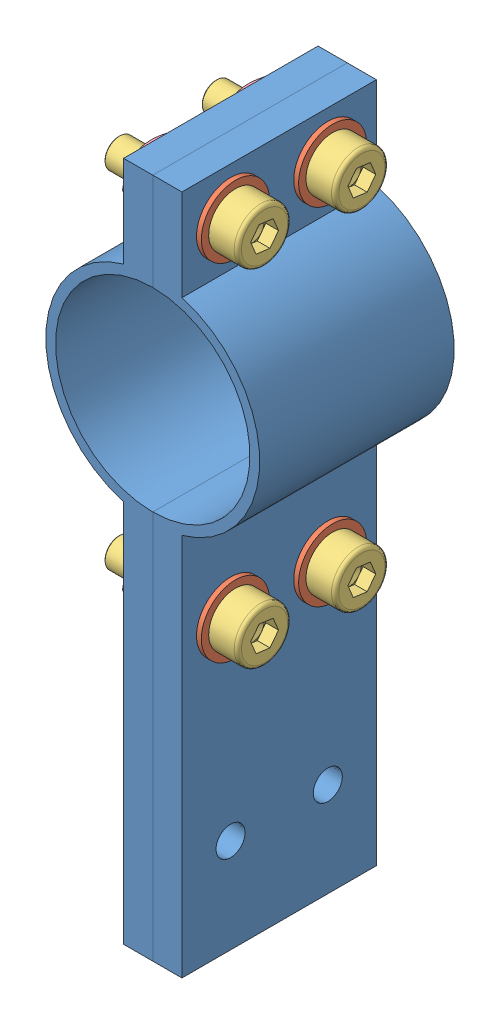
SolidWorks assembly 小管夹具, configuration 默认. Lengths in mm.
Overall size (22 70 20).
14 component instances, 4 part files, 28 mates.
Components (placement in the parent):
- 夹具-1: 夹具 [默认] at (55.615 31.0944 -10) size (11 70 20)
- 夹具-2: 夹具 [默认] at (55.615 31.0944 10) x (-1 0 0) z (0 0 -1) size (11 70 20)
- plain washers-n series-grade a gb-2: plain washers-n series-grade a gb [GB_FASTENER_WASHER_PWNA 3] at (59.115 46.3859 5) x (0 0 -1) z (1 0 0) size (7 7 0.5)
- plain washers-n series-grade a gb-3: plain washers-n series-grade a gb [GB_FASTENER_WASHER_PWNA 3] at (59.115 46.3859 -5) x (0 0 -1) z (1 0 0) size (7 7 0.5)
- plain washers-n series-grade a gb-4: plain washers-n series-grade a gb [GB_FASTENER_WASHER_PWNA 3] at (59.115 10.8029 -5) x (0 0 -1) z (1 0 0) size (7 7 0.5)
- plain washers-n series-grade a gb-5: plain washers-n series-grade a gb [GB_FASTENER_WASHER_PWNA 3] at (59.115 10.8029 5) x (0 0 -1) z (1 0 0) size (7 7 0.5)
- hexagon socket head cap screws gb-2: hexagon socket head cap screws gb [GB_FASTENER_SCREWS_HSHCS M3X12-N] at (62.115 10.8029 -5) x (-1 0 0) z (0 0.924225 0.381849) size (15 5.5 5.5)
- hexagon socket head cap screws gb-3: hexagon socket head cap screws gb [GB_FASTENER_SCREWS_HSHCS M3X12-N] at (62.115 10.8029 5) x (-1 0 0) z (0 0.924225 0.381849) size (15 5.5 5.5)
- hexagon socket head cap screws gb-4: hexagon socket head cap screws gb [GB_FASTENER_SCREWS_HSHCS M3X12-N] at (62.115 46.3859 -5) x (-1 0 0) z (0 0.924225 0.381849) size (15 5.5 5.5)
- hexagon socket head cap screws gb-5: hexagon socket head cap screws gb [GB_FASTENER_SCREWS_HSHCS M3X12-N] at (62.115 46.3859 5) x (-1 0 0) z (0 0.924225 0.381849) size (15 5.5 5.5)
- hex nuts, style 1-grades ab gb-2: hex nuts, style 1-grades ab gb [GB_FASTENER_NUT_SNAB1 M3-N] at (50.215 10.8029 -5) x (0 0 1) z (-1 0 0) size (6.35 5.5 2.4)
- hex nuts, style 1-grades ab gb-3: hex nuts, style 1-grades ab gb [GB_FASTENER_NUT_SNAB1 M3-N] at (50.215 10.8029 5) x (0 0 1) z (-1 0 0) size (6.35 5.5 2.4)
- hex nuts, style 1-grades ab gb-4: hex nuts, style 1-grades ab gb [GB_FASTENER_NUT_SNAB1 M3-N] at (50.215 46.3859 -5) x (0 0 1) z (-1 0 0) size (6.35 5.5 2.4)
- hex nuts, style 1-grades ab gb-5: hex nuts, style 1-grades ab gb [GB_FASTENER_NUT_SNAB1 M3-N] at (50.215 46.3859 5) x (0 0 1) z (-1 0 0) size (6.35 5.5 2.4)
Mates (geometry in assembly coordinates):
- 同心1: concentric anti-aligned: cylinder of 夹具-1 through (72.615 46.3859 5) axis (-1 0 0) radius 1.5; cylinder of 夹具-2 through (38.615 46.3859 5) axis (1 0 0) radius 1.5
- 同心2: concentric anti-aligned: cylinder of 夹具-1 through (72.615 46.3859 -5) axis (-1 0 0) radius 1.5; cylinder of 夹具-2 through (38.615 46.3859 -5) axis (1 0 0) radius 1.5
- 同心3: concentric anti-aligned: cylinder of 夹具-1 through (72.615 10.8029 5) axis (-1 0 0) radius 1.5; cylinder of 夹具-2 through (38.615 10.8029 5) axis (1 0 0) radius 1.5
- 重合1: coincident anti-aligned: plane of 夹具-1 through (55.615 31.0944 10) normal (1 0 0); plane of 夹具-2 through (55.615 31.0944 -10) normal (-1 0 0)
- 同心4: concentric aligned: cylinder of 夹具-2 through (38.615 46.3859 5) axis (1 0 0) radius 1.5; cylinder of plain washers-n series-grade a gb-2 through (58.615 46.3859 5) axis (1 0 0) radius 1.6
- 重合2: coincident anti-aligned: plane of 夹具-2 through (58.615 31.0944 -10) normal (1 0 0); plane of plain washers-n series-grade a gb-2 through (58.615 46.3859 5) normal (-1 0 0)
- 同心5: concentric aligned: cylinder of 夹具-2 through (38.615 46.3859 -5) axis (1 0 0) radius 1.5; cylinder of plain washers-n series-grade a gb-3 through (58.615 46.3859 -5) axis (1 0 0) radius 1.6
- 重合3: coincident anti-aligned: plane of 夹具-2 through (58.615 31.0944 -10) normal (1 0 0); plane of plain washers-n series-grade a gb-3 through (58.615 46.3859 -5) normal (-1 0 0)
- 同心6: concentric aligned: cylinder of 夹具-2 through (38.615 10.8029 -5) axis (1 0 0) radius 1.5; cylinder of plain washers-n series-grade a gb-4 through (58.615 10.8029 -5) axis (1 0 0) radius 1.6
- 重合4: coincident anti-aligned: plane of 夹具-2 through (58.615 31.0944 -10) normal (1 0 0); plane of plain washers-n series-grade a gb-4 through (58.615 10.8029 -5) normal (-1 0 0)
- 同心7: concentric aligned: cylinder of 夹具-2 through (38.615 10.8029 5) axis (1 0 0) radius 1.5; cylinder of plain washers-n series-grade a gb-5 through (58.615 10.8029 5) axis (1 0 0) radius 1.6
- 重合5: coincident anti-aligned: plane of 夹具-2 through (58.615 31.0944 -10) normal (1 0 0); plane of plain washers-n series-grade a gb-5 through (58.615 10.8029 5) normal (-1 0 0)
- 同心8: concentric aligned: cylinder of 夹具-2 through (38.615 10.8029 -5) axis (1 0 0) radius 1.5; cylinder of hexagon socket head cap screws gb-2 through (47.115 10.8029 -5) axis (1 0 0) radius 1.5
- 重合6: coincident anti-aligned: plane of plain washers-n series-grade a gb-4 through (59.115 10.8029 -5) normal (1 0 0); plane of hexagon socket head cap screws gb-2 through (59.115 10.8029 -5) normal (-1 0 0)
- 同心9: concentric aligned: cylinder of 夹具-2 through (38.615 10.8029 5) axis (1 0 0) radius 1.5; cylinder of hexagon socket head cap screws gb-3 through (47.115 10.8029 5) axis (1 0 0) radius 1.5
- 重合7: coincident anti-aligned: plane of plain washers-n series-grade a gb-5 through (59.115 10.8029 5) normal (1 0 0); plane of hexagon socket head cap screws gb-3 through (59.115 10.8029 5) normal (-1 0 0)
- 同心10: concentric aligned: cylinder of 夹具-2 through (38.615 46.3859 -5) axis (1 0 0) radius 1.5; cylinder of hexagon socket head cap screws gb-4 through (47.115 46.3859 -5) axis (1 0 0) radius 1.5
- 重合8: coincident anti-aligned: plane of plain washers-n series-grade a gb-3 through (59.115 46.3859 -5) normal (1 0 0); plane of hexagon socket head cap screws gb-4 through (59.115 46.3859 -5) normal (-1 0 0)
- 同心11: concentric aligned: cylinder of 夹具-2 through (38.615 46.3859 5) axis (1 0 0) radius 1.5; cylinder of hexagon socket head cap screws gb-5 through (47.115 46.3859 5) axis (1 0 0) radius 1.5
- 重合9: coincident anti-aligned: plane of plain washers-n series-grade a gb-2 through (59.115 46.3859 5) normal (1 0 0); plane of hexagon socket head cap screws gb-5 through (59.115 46.3859 5) normal (-1 0 0)
- 同心12: concentric anti-aligned: cylinder of hexagon socket head cap screws gb-2 through (47.115 10.8029 -5) axis (1 0 0) radius 1.5; cone of hex nuts, style 1-grades ab gb-2 through (52.615 10.8029 -5) axis (-1 0 0)
- 重合10: coincident anti-aligned: plane of 夹具-1 through (52.615 31.0944 10) normal (-1 0 0); plane of hex nuts, style 1-grades ab gb-2 through (52.615 5.3029 -5) normal (1 0 0)
- 同心13: concentric anti-aligned: cylinder of hexagon socket head cap screws gb-3 through (47.115 10.8029 5) axis (1 0 0) radius 1.5; cone of hex nuts, style 1-grades ab gb-3 through (52.615 10.8029 5) axis (-1 0 0)
- 重合11: coincident anti-aligned: plane of 夹具-1 through (52.615 31.0944 10) normal (-1 0 0); plane of hex nuts, style 1-grades ab gb-3 through (52.615 5.3029 5) normal (1 0 0)
- 同心14: concentric anti-aligned: cylinder of hexagon socket head cap screws gb-4 through (47.115 46.3859 -5) axis (1 0 0) radius 1.5; cone of hex nuts, style 1-grades ab gb-4 through (52.615 46.3859 -5) axis (-1 0 0)
- 重合12: coincident anti-aligned: plane of 夹具-1 through (52.615 31.0944 10) normal (-1 0 0); plane of hex nuts, style 1-grades ab gb-4 through (52.615 40.8859 -5) normal (1 0 0)
- 同心15: concentric anti-aligned: cylinder of hexagon socket head cap screws gb-5 through (47.115 46.3859 5) axis (1 0 0) radius 1.5; cone of hex nuts, style 1-grades ab gb-5 through (52.615 46.3859 5) axis (-1 0 0)
- 重合13: coincident anti-aligned: plane of 夹具-1 through (52.615 31.0944 10) normal (-1 0 0); plane of hex nuts, style 1-grades ab gb-5 through (52.615 40.8859 5) normal (1 0 0)
